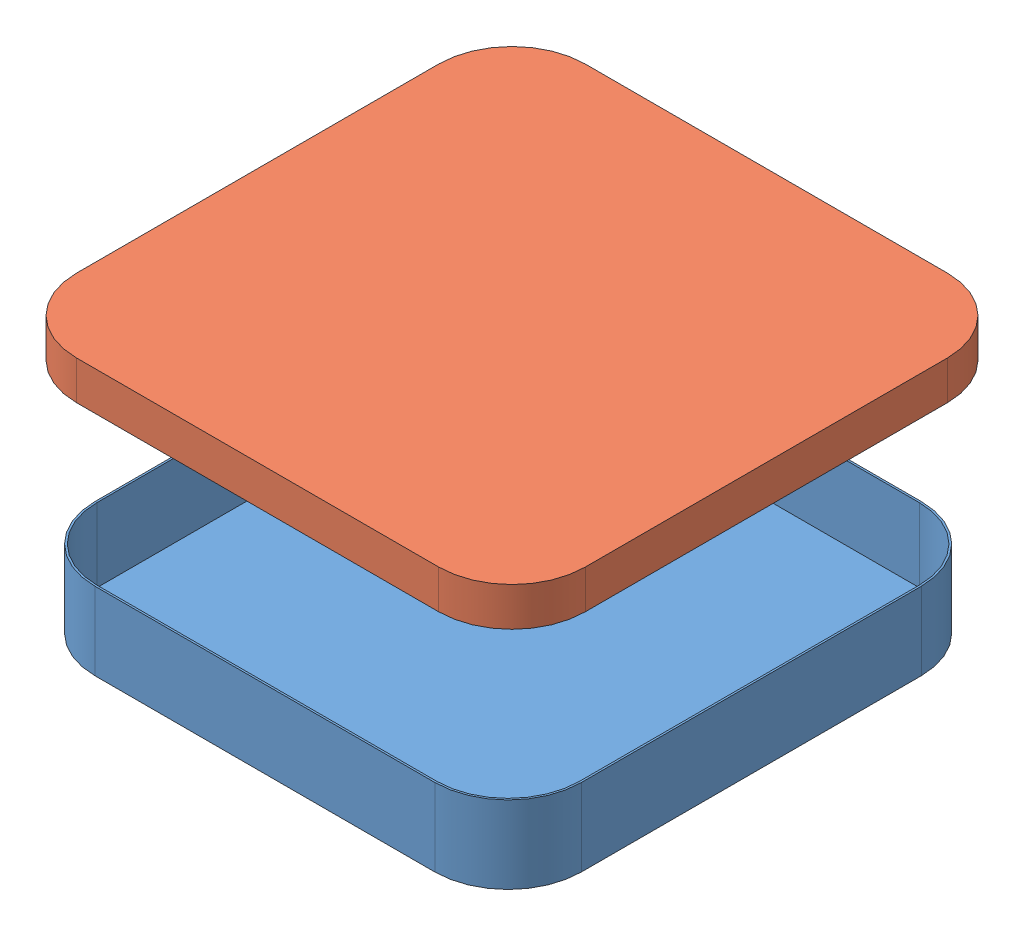
SolidWorks assembly Culture_Cell_boite_3, configuration Défaut. Lengths in mm.
Overall size (262.5 142 262.5).
2 component instances, 2 part files, 5 mates.
Components (placement in the parent):
- Boite-1: Boite [Défaut] at origin size (250.95 40 250.95)
- Couvercle-2: Couvercle [Défaut] at (257.725 142 4.775) x (-1 0 0) z (0 0 1) size (262.5 20 262.5)
Mates (geometry in assembly coordinates):
- Parallèle1: parallel anti-aligned: plane of Boite-1 through (37.8 40 -213.15) normal (0 1 0); plane of Couvercle-2 through (33.025 140 -219.925) normal (0 -1 0)
- Parallèle2: parallel aligned: plane of Boite-1 through (37.8 40 0) normal (0 0 1); plane of Couvercle-2 through (33.025 122 4.775) normal (0 0 1)
- Distance2: distance = 3.775 mm anti-aligned: plane of Boite-1 through (37.8 40 0) normal (0 0 1); plane of Couvercle-2 through (219.925 140 3.775) normal (0 0 -1)
- Distance3: distance = 3.775 mm anti-aligned: plane of Boite-1 through (0 40 -213.15) normal (-1 0 0); plane of Couvercle-2 through (-3.775 140 -33.025) normal (1 0 0)
- DistanceLimite1: limit distance = 100 mm anti-aligned: plane of Couvercle-2 through (33.025 140 -219.925) normal (0 -1 0); plane of Boite-1 through (37.8 40 -213.15) normal (0 1 0)
